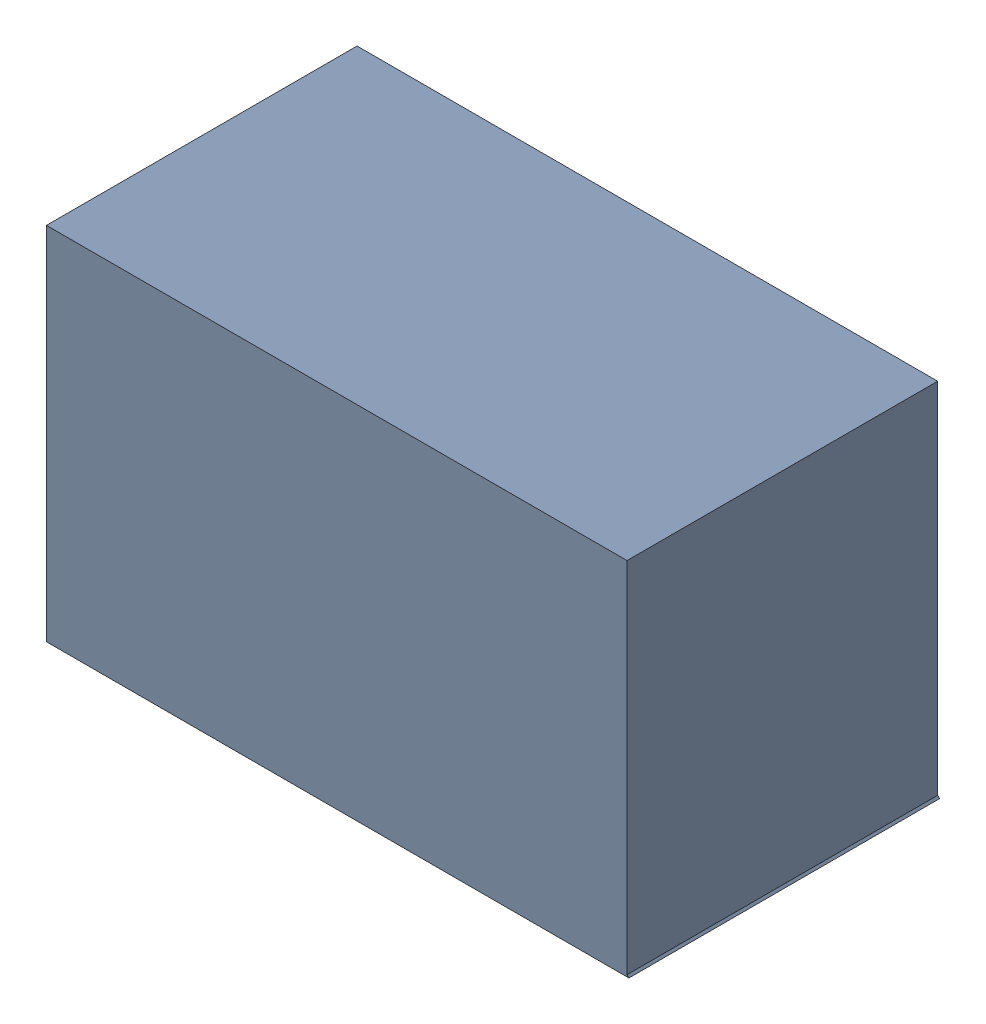
SolidWorks assembly U3, configuration Default. Lengths in mm.
Overall size (2.01 1.25 1.08).
2 component instances, 1 part files, 0 mates.
Components (placement in the parent):
- 948828536-1: 948828536 [Default] at (35.1133 2.9762 0) size (2.01 1.25 1.08)
  - Extruded_17-1: Extruded_17 [Default] at origin size (2.01 1.25 1.08)
